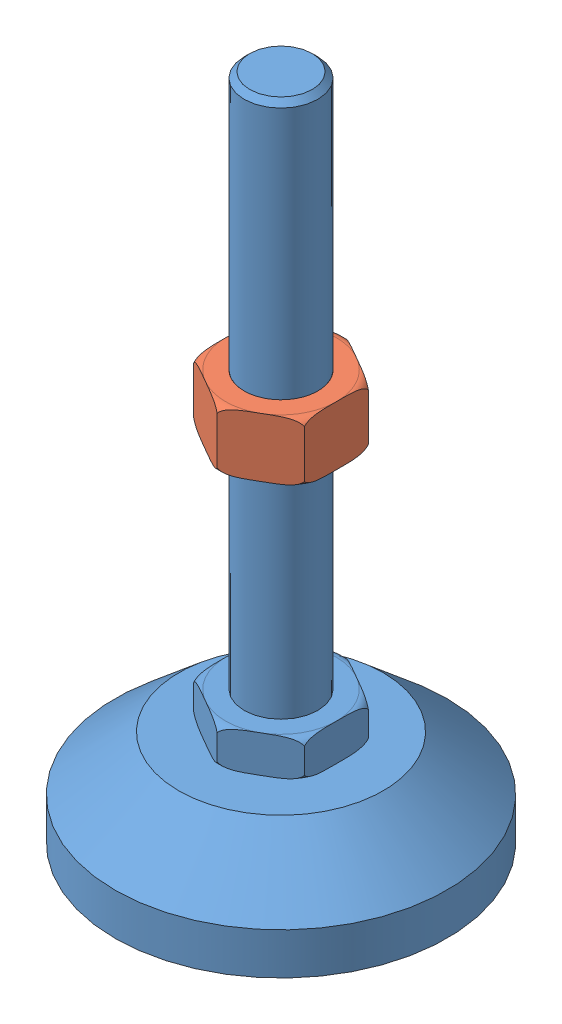
SolidWorks assembly BZR01-8020150, configuration 默认. Lengths in mm.
Overall size (90 181 90).
2 component instances, 2 part files, 0 mates.
Components (placement in the parent):
- _BZR01-8020150-001                                                                            30 20.3 8020150-1: _BZR01-8020150-001                                                                            30 20.3 8020150 [默认] at (0 -114 0) size (90 181 90)
- _BZR01-8020150-002                                                                            30 20.3 8020150-1: _BZR01-8020150-002                                                                            30 20.3 8020150 [默认] at (0 -114 0) size (30.02 16.02 34.66)
